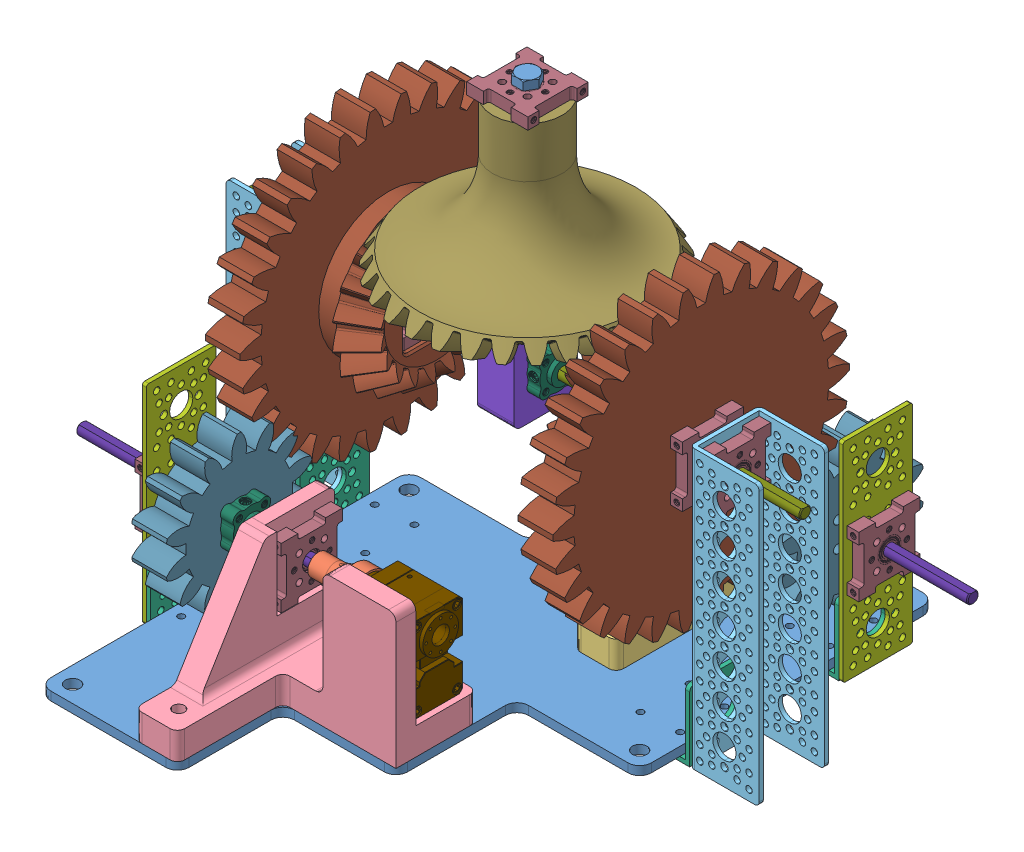
SolidWorks assembly ARMUS-103-000, configuration Défaut. Lengths in mm.
Overall size (324.91 266.38 286.64).
47 component instances, 19 part files, 72 mates.
Components (placement in the parent):
- ARMUS-103-001_V2-1: ARMUS-103-001_V2 [Default] at (0 -175.0433 0) size (204.98 4.76 285.62)
- ARMUS-103-002-1: ARMUS-103-002 [Default] at (4.7543 -124.9418 -81.7535) x (0 -0.707107 -0.707107) z (0 -0.707107 0.707107) size (22.05 28 22.05)
- ARMUS-103-003-1: ARMUS-103-003 [Défaut] at (-18.3357 -176.9255 -20.4725) size (85.41 73.38 122.11)
- ARMUS-103-004-2: ARMUS-103-004 [Défaut] at (52.1557 -176.9255 143.0345) size (85.41 73.38 122.11)
- ARMUS-103-005-2: ARMUS-103-005 [Default] at (107.9493 -29.6918 19.05) x (0 0 -1) z (0 -1 0) size (38.1 38.1 152.4)
- ARMUS-103-006-2: ARMUS-103-006 [Default] at (88.8993 -182.0918 0) x (0 0 -1) z (1 0 0) size (38.1 38.1 38.1)
- ARMUS-103-006-5: ARMUS-103-006 [Default] at (88.8993 -182.0918 -81.7535) x (0 0 -1) z (1 0 0) size (38.1 38.1 38.1)
- ARMUS-103-007-2: ARMUS-103-007 [Default] at (110.2353 -143.9918 -81.7535) x (0 -1 0) z (0 0 -1) size (114.3 2.29 38.1)
- ARMUS-103-200-1: ARMUS-103-200 [Défaut] at (0 -48.7418 17.5) x (0 1 0) z (-1 0 0) size (54 35 20)
  - ARMUS-REV4-201-1: ARMUS-REV4-201 [Défaut] at origin size (54 35 20)
  - HUB-0_25-1: HUB-0_25 [Défaut] at (-30.0172 37.5992 -6.2696) x (-1 0 0) z (0 -1 0) size (25.4 12.7 25.4)
  - hex nut_ai-2: hex nut_ai [HNUT 0.2500-20-D-N] at (19.3798 17.5 0) x (0 0.5 0.866025) z (-1 0 0) size (11.11 12.83 5.74)
- ARMUS-103-301-1: ARMUS-103-301 [Default] at (76.1993 -48.7418 0) size (50.86 161.95 162.56)
- ARMUS-103-400-1: ARMUS-103-400 [Défaut] x (0 -1 0) z (0 0 -1) size (128.27 130.43 130.79)
  - ARMUS-REV4-401-1: ARMUS-REV4-401 [Default] at origin size (93.2 130.43 130.79)
  - Bore Side Tapped Pillow Block 1.25-1: Bore Side Tapped Pillow Block 1.25 [Default] at (-58.9626 7.6184 28.3917) x (0 -1 0) z (0 0 -1) size (33.54 6.35 33.02)
  - Bore Side Tapped Pillow Block 1.25-2: Bore Side Tapped Pillow Block 1.25 [Default] at (26.0822 -28.3917 7.6184) x (0 0 -1) z (0 1 0) size (33.54 6.35 33.02)
- ARMUS-103-500-1: ARMUS-103-500 [Défaut] at (76.1993 -124.9425 -81.7542) x (1 0 0) z (0 1 0) size (28.58 79.69 81.28)
  - ARMUS-REV4-501-1: ARMUS-REV4-501 [Défaut] at origin size (19.05 79.69 81.28)
  - bore_set_screw_D_hub-1: bore_set_screw_D_hub [Défaut] at (-20.7023 -52.5937 -16.7801) x (0 -1 0.000796) z (0 0.000796 1) size (20.57 9.61 20.57)
- bore_set_screw_D_hub-1: bore_set_screw_D_hub [Défaut] at (-30.7023 -31.9192 -52.5797) x (0 0 -1) z (0 -1 0) size (20.57 9.61 20.57)
- bore_set_screw_D_hub-2: bore_set_screw_D_hub [Défaut] at (30.7023 3.8379 -16.8226) x (0 1 0) z (0 0 1) size (20.57 9.61 20.57)
- Bore Side Tapped Pillow Block 1.25-1: Bore Side Tapped Pillow Block 1.25 [Default] at (36.7834 -77.1335 -7.6184) x (0 0 1) z (0 1 0) size (33.54 6.35 33.02)
- Bore Side Tapped Pillow Block 1.25-2: Bore Side Tapped Pillow Block 1.25 [Default] at (81.0339 -77.1335 -7.6184) x (0 0 1) z (0 1 0) size (33.54 6.35 33.02)
- Bore Side Tapped Pillow Block 1.25-3: Bore Side Tapped Pillow Block 1.25 [Default] at (22.1889 -153.3335 -89.3719) x (0 0 1) z (0 1 0) size (33.54 6.35 33.02)
- Bore Side Tapped Pillow Block 1.25-4: Bore Side Tapped Pillow Block 1.25 [Default] at (96.0199 -153.3335 -89.3719) x (0 0 1) z (0 1 0) size (33.54 6.35 33.02)
- Bore Side Tapped Pillow Block 1.25-5: Bore Side Tapped Pillow Block 1.25 [Default] at (96.0199 -77.1335 -7.6184) x (0 0 1) z (0 1 0) size (33.54 6.35 33.02)
- D-Shaft 1.25x8-1: D-Shaft 1.25x8 [Default] at (0 -48.7418 0) x (0 0 1) z (1 0 0) size (6.35 5.71 304.8)
- D-Shaft 1.25x6-1: D-Shaft 1.25x6 [Default] at (86.2543 -124.9418 -81.7535) x (0 0.000796 1) z (1 0 0) size (6.35 5.71 152.4)
- XM430-W350-R-1: XM430-W350-R [Default] at (-14.6539 -136.2662 -82.2402) x (0 0 -1) z (1 0 0) size (28.5 46.5 41)
- hex bolt_ai-1: hex bolt_ai [HBOLT 0.2500-20x4.5x0.75-N] at (0 84.2906 0) x (0 -1 0) z (-0.866025 0 0.5) size (119.08 12.85 11.13)
- ARMUS-103-006-4: ARMUS-103-006 [Default] at (-88.8993 -182.0918 0) x (0 0 1) z (-1 0 0) size (38.1 38.1 38.1)
- ARMUS-103-006-6: ARMUS-103-006 [Default] at (-88.8993 -182.0918 81.7535) x (0 0 1) z (-1 0 0) size (38.1 38.1 38.1)
- XM430-W350-R-2: XM430-W350-R [Default] at (14.6539 -136.2662 82.2402) x (0 0 1) z (-1 0 0) size (28.5 46.5 41)
- ARMUS-103-002-2: ARMUS-103-002 [Default] at (-4.7543 -124.9418 81.7535) x (0 -0.707107 0.707107) z (0 -0.707107 -0.707107) size (22.05 28 22.05)
- Bore Side Tapped Pillow Block 1.25-6: Bore Side Tapped Pillow Block 1.25 [Default] at (-22.1889 -153.3335 89.3719) x (0 0 -1) z (0 1 0) size (33.54 6.35 33.02)
- Bore Side Tapped Pillow Block 1.25-7: Bore Side Tapped Pillow Block 1.25 [Default] at (-36.7834 -77.1335 7.6184) x (0 0 -1) z (0 1 0) size (33.54 6.35 33.02)
- ARMUS-103-500-2: ARMUS-103-500 [Défaut] at (-76.1993 -124.9425 81.7542) x (-1 0 0) z (0 1 0) size (28.58 79.69 81.28)
  - ARMUS-REV4-501-1: ARMUS-REV4-501 [Défaut] at origin size (19.05 79.69 81.28)
  - bore_set_screw_D_hub-1: bore_set_screw_D_hub [Défaut] at (-20.7023 -52.5937 -16.7801) x (0 -1 0.000796) z (0 0.000796 1) size (20.57 9.61 20.57)
- ARMUS-103-301-2: ARMUS-103-301 [Default] at (-76.1993 -48.7418 0) x (-1 0 0) z (0 0 -1) size (50.86 161.95 162.56)
- D-Shaft 1.25x6-2: D-Shaft 1.25x6 [Default] at (-86.2543 -124.9418 81.7535) x (0 0.000796 -1) z (-1 0 0) size (6.35 5.71 152.4)
- Bore Side Tapped Pillow Block 1.25-8: Bore Side Tapped Pillow Block 1.25 [Default] at (-81.0339 -77.1335 7.6184) x (0 0 -1) z (0 1 0) size (33.54 6.35 33.02)
- Bore Side Tapped Pillow Block 1.25-9: Bore Side Tapped Pillow Block 1.25 [Default] at (-96.0199 -77.1335 7.6184) x (0 0 -1) z (0 1 0) size (33.54 6.35 33.02)
- Bore Side Tapped Pillow Block 1.25-10: Bore Side Tapped Pillow Block 1.25 [Default] at (-96.0199 -153.3335 89.3719) x (0 0 -1) z (0 1 0) size (33.54 6.35 33.02)
- ARMUS-103-005-3: ARMUS-103-005 [Default] at (-107.9493 -29.6918 -19.05) x (0 0 1) z (0 -1 0) size (38.1 38.1 152.4)
- ARMUS-103-007-3: ARMUS-103-007 [Default] at (-110.2353 -143.9918 81.7535) x (0 -1 0) z (0 0 1) size (114.3 2.29 38.1)
Mates (geometry in assembly coordinates):
- Tangent1: tangent: circle of ARMUS-REV4-301-1; circle of ARMUS-REV4-500-1
- Coincident4: coincident aligned: plane of ARMUS-REV4-301-1 through (76.1993 -48.7418 0) normal (-1 0 0); plane of ARMUS-REV4-500-1/ARMUS-REV4-501-1 through (76.1993 -124.9425 -81.7542) normal (-1 0 0)
- Parallel3: parallel aligned: plane of ARMUS-REV4-301-1 through (76.1993 -48.7418 0) normal (0 1 0); plane of ARMUS-REV4-500-1 through (76.1993 -124.9425 -81.7542) normal (0 1 0)
- Concentric2: concentric anti-aligned: cylinder of ARMUS-REV4-301-1 through (-9.9286 -48.7418 0) axis (1 0 0) radius 6.35; cylinder of ARMUS-REV4-012-1 through (107.9493 -48.7418 0) axis (-1 0 0) radius 6.3627
- Parallel4: parallel aligned: plane of ARMUS-REV4-301-1 through (56.0789 -30.7078 -16.51) normal (0 -1 0); plane of ARMUS-REV4-012-1 through (107.9493 -182.0918 19.05) normal (0 -1 0)
- Distance1: distance = 12.7 mm anti-aligned: plane of ARMUS-REV4-301-1 through (95.2493 -48.7418 0) normal (1 0 0); plane of ARMUS-REV4-012-1 through (107.9493 -182.0918 -19.05) normal (-1 0 0)
- Concentric3: concentric anti-aligned: cylinder of ARMUS-REV4-301-1 through (-9.9286 -48.7418 0) axis (1 0 0) radius 6.35; cylinder of Bore Side Tapped Pillow Block 1.25-1 through (57.3362 -48.7418 0) axis (-1 0 0) radius 3.175
- Concentric4: concentric anti-aligned: cylinder of ARMUS-REV4-301-1 through (49.7289 -41.827 -6.9148) axis (-1 0 0) radius 1.25; cylinder of Bore Side Tapped Pillow Block 1.25-1 through (57.3489 -41.827 -6.9148) axis (1 0 0) radius 1.778
- Coincident5: coincident anti-aligned: plane of ARMUS-REV4-301-1 through (57.3489 -48.7418 0) normal (-1 0 0); plane of Bore Side Tapped Pillow Block 1.25-1 through (57.3489 -48.7418 0) normal (1 0 0)
- Concentric5: concentric anti-aligned: cylinder of ARMUS-REV4-301-1 through (-9.9286 -48.7418 0) axis (1 0 0) radius 6.35; cylinder of Bore Side Tapped Pillow Block 1.25-2 through (101.5866 -48.7418 0) axis (-1 0 0) radius 3.175
- Concentric6: concentric anti-aligned: cylinder of ARMUS-REV4-301-1 through (49.7289 -41.827 6.9148) axis (-1 0 0) radius 1.25; cylinder of Bore Side Tapped Pillow Block 1.25-2 through (101.5993 -41.827 6.9148) axis (1 0 0) radius 1.778
- Coincident6: coincident anti-aligned: plane of ARMUS-REV4-301-1 through (95.2493 -48.7418 0) normal (1 0 0); plane of Bore Side Tapped Pillow Block 1.25-2 through (95.2493 -48.7418 0) normal (-1 0 0)
- Concentric7: concentric anti-aligned: cylinder of ARMUS-REV4-012-1 through (107.9493 -163.0418 0) axis (-1 0 0) radius 6.3627; cylinder of ARMUS-REV4-010-2 through (107.9493 -163.0418 0) axis (1 0 0) radius 6.3627
- Coincident7: coincident aligned: plane of ARMUS-REV4-012-1 through (107.9493 -182.0918 19.05) normal (0 -1 0); plane of ARMUS-REV4-010-2 through (88.8993 -182.0918 0) normal (0 -1 0)
- Coincident8: coincident anti-aligned: plane of ARMUS-REV4-012-1 through (107.9493 -182.0918 -19.05) normal (-1 0 0); plane of ARMUS-REV4-010-2 through (107.9493 -179.8058 19.05) normal (1 0 0)
- Coincident9: coincident aligned: plane of ARMUS-REV4-010-2 through (88.8993 -182.0918 0) normal (0 -1 0); plane of ARMUS-REV4-010-3 through (88.8993 -182.0918 -81.7535) normal (0 -1 0)
- Coincident10: coincident aligned: plane of ARMUS-REV4-010-2 through (105.6633 -182.0918 0) normal (-1 0 0); plane of ARMUS-REV4-010-3 through (105.6633 -182.0918 -81.7535) normal (-1 0 0)
- Concentric8: concentric anti-aligned: cylinder of ARMUS-REV4-011-2 through (107.9493 -163.0418 -81.7535) axis (-1 0 0) radius 6.3627; cylinder of ARMUS-REV4-010-3 through (107.9493 -163.0418 -81.7535) axis (1 0 0) radius 6.3627
- Coincident11: coincident anti-aligned: plane of ARMUS-REV4-011-2 through (107.9493 -143.9918 -81.7535) normal (-1 0 0); plane of ARMUS-REV4-010-3 through (107.9493 -179.8058 -62.7035) normal (1 0 0)
- Concentric9: concentric anti-aligned: cylinder of ARMUS-REV4-500-1/bore_set_screw_D_hub-1 through (76.1993 -124.9418 -81.7535) axis (1 0 0) radius 3.175; cylinder of ARMUS-REV4-011-2 through (107.9493 -124.9418 -81.7535) axis (-1 0 0) radius 6.3627
- Coincident12: coincident aligned: plane of ARMUS-REV4-011-2 through (107.9493 -182.0918 -100.8035) normal (0 -1 0); plane of ARMUS-REV4-010-3 through (88.8993 -182.0918 -81.7535) normal (0 -1 0)
- Coincident16: coincident: line of ARMUS-REV4-400-1/ARMUS-REV4-401-1 through (0 73.1781 0) axis (0 -1 0)
- Coincident18: coincident: unknown of ARMUS-REV4-400-1
- Parallel5: parallel anti-aligned: plane of ARMUS-REV4-400-1/ARMUS-REV4-401-1 through (0 -12.1668 0) normal (0 -1 0)
- Coincident19: coincident: point of ARMUS-103-400-1/ARMUS-REV4-401-1; point of ARMUS-103-301-1
- Coincident21: coincident anti-aligned: plane of ARMUS-REV4-400-1 through (0 0 0) normal (0 0 -1)
- Perpendicular2: perpendicular: plane of ARMUS-REV4-400-1/ARMUS-REV4-401-1 through (0 -12.1668 0) normal (0 -1 0); plane of ARMUS-REV4-301-1 through (49.7289 -48.7418 0) normal (-1 0 0)
- Parallel6: parallel aligned: plane of ARMUS-REV4-301-1 through (76.1993 -48.7418 0) normal (1 0 0)
- Parallel7: parallel aligned: plane of ARMUS-REV4-400-1/ARMUS-REV4-401-1 through (0 -12.1668 0) normal (0 -1 0); plane of ARMUS-REV4-010-3 through (88.8993 -182.0918 -81.7535) normal (0 -1 0)
- Concentric10: concentric anti-aligned: cylinder of Bore Side Tapped Pillow Block 1.25-1 through (57.3362 -48.7418 0) axis (-1 0 0) radius 3.175; cylinder of D-Shaft 1.25x8-1 through (-152.4 -48.7418 0) axis (1 0 0) radius 3.175
- Parallel8: parallel anti-aligned: plane of ARMUS-REV4-400-1/ARMUS-REV4-401-1 through (0 -12.1668 0) normal (0 -1 0); plane of D-Shaft 1.25x8-1 through (-152.4 -46.2018 -1.905) normal (0 1 0)
- Concentric11: concentric anti-aligned: cylinder of ARMUS-REV4-200-1/HUB-0_25-1 through (6.35 -48.7418 0) axis (-1 0 0) radius 3.175; cylinder of D-Shaft 1.25x8-1 through (-152.4 -48.7418 0) axis (1 0 0) radius 3.175
- Concentric12: concentric aligned: cylinder of ARMUS-REV4-400-1/ARMUS-REV4-401-1 through (0 -128.2701 0) axis (0 1 0) radius 6.35; cylinder of ARMUS-REV4-200-1/ARMUS-REV4-201-1 through (0 -43.222 0) axis (0 1 0) radius 3.175
- Concentric13: concentric aligned: cylinder of bore_set_screw_D_hub-1 through (-10 -48.7418 0) axis (1 0 0) radius 3.175; cylinder of D-Shaft 1.25x8-1 through (-152.4 -48.7418 0) axis (1 0 0) radius 3.175
- Concentric14: concentric aligned: cylinder of ARMUS-REV4-200-1/ARMUS-REV4-201-1 through (15.0289 -41.827 -6.9148) axis (-1 0 0) radius 1.778; cylinder of bore_set_screw_D_hub-1 through (-10 -41.827 -6.9148) axis (-1 0 0) radius 3.3722
- Coincident23: coincident anti-aligned: plane of ARMUS-REV4-200-1/ARMUS-REV4-201-1 through (-10 -18.7418 -17.5) normal (-1 0 0); plane of bore_set_screw_D_hub-1 through (-10 -45.2844 3.4574) normal (1 0 0)
- Coincident24: coincident anti-aligned: plane of ARMUS-REV4-200-1/ARMUS-REV4-201-1 through (10 -18.7418 -17.5) normal (1 0 0); plane of bore_set_screw_D_hub-2 through (10 -52.1992 -3.4574) normal (-1 0 0)
- Concentric15: concentric anti-aligned: cylinder of ARMUS-REV4-200-1/ARMUS-REV4-201-1 through (15.0289 -55.6566 -6.9148) axis (-1 0 0) radius 1.778; cylinder of bore_set_screw_D_hub-2 through (10 -55.6566 -6.9148) axis (1 0 0) radius 3.3722
- Concentric16: concentric anti-aligned: cylinder of bore_set_screw_D_hub-2 through (10 -48.7418 0) axis (-1 0 0) radius 3.175; cylinder of D-Shaft 1.25x8-1 through (-152.4 -48.7418 0) axis (1 0 0) radius 3.175
- Width1: width aligned: plane of D-Shaft 1.25x8-1 through (-152.4 -48.7418 0) normal (-1 0 0); plane of ARMUS-REV4-200-1/ARMUS-REV4-201-1 through (152.4 -48.7418 0) normal (1 0 0); plane of D-Shaft 1.25x8-1 through (-10 -18.7418 -17.5) normal (-1 0 0); plane of ARMUS-REV4-200-1/ARMUS-REV4-201-1 through (10 -18.7418 -17.5) normal (1 0 0)
- Concentric17: concentric anti-aligned: cylinder of ARMUS-REV4-500-1/bore_set_screw_D_hub-1 through (76.1993 -124.9418 -81.7535) axis (1 0 0) radius 3.175; cylinder of ARMUS-REV4-004-1 through (83.1653 -124.9418 -81.7535) axis (-1 0 0) radius 4.5
- Parallel9: parallel anti-aligned: plane of ARMUS-REV4-010-3 through (88.8993 -179.8058 -81.7535) normal (0 1 0); plane of ARMUS-REV4-004-1 through (-84.6557 -175.0433 114.7662) normal (0 -1 0)
- Distance2: distance = 19.05 mm anti-aligned: plane of ARMUS-REV4-500-1/bore_set_screw_D_hub-1 through (69.2143 -128.4019 -85.2081) normal (-1 0 0); plane of ARMUS-REV4-004-1 through (50.1643 -101.6652 -100.5825) normal (1 0 0)
- Concentric18: concentric aligned: cylinder of ARMUS-REV4-004-1 through (-9.2457 -175.0433 -89.7535) axis (0 1 0) radius 1; cylinder of XM430-W350-R-1 through (-9.2457 -157.1918 -89.7535) axis (0 1 0) radius 1
- Concentric19: concentric aligned: cylinder of ARMUS-REV4-004-1 through (-21.2457 -175.0433 -89.7535) axis (0 1 0) radius 1; cylinder of XM430-W350-R-1 through (-21.2457 -157.1918 -89.7535) axis (0 1 0) radius 1
- Coincident25: coincident anti-aligned: plane of ARMUS-REV4-004-1 through (-35.2457 -160.1918 -56.2023) normal (0 1 0); plane of XM430-W350-R-1 through (-6.7457 -160.1918 -67.5035) normal (0 -1 0)
- Concentric20: concentric anti-aligned: cylinder of ARMUS-REV4-004-1 through (83.1653 -124.9418 -81.7535) axis (-1 0 0) radius 4.5; cylinder of XM430-W350-R-1 through (4.7543 -124.9418 -81.7535) axis (1 0 0) radius 9.75
- Concentric21: concentric anti-aligned: cylinder of XM430-W350-R-1 through (4.7543 -124.9418 -81.7535) axis (1 0 0) radius 9.75; cylinder of ARMUS-REV4-002-1 through (12.7543 -124.9418 -81.7535) axis (-1 0 0) radius 10.75
- Concentric22: concentric anti-aligned: circle of XM430-W350-R-1; cylinder of ARMUS-REV4-002-1 through (12.7543 -116.9418 -81.7535) axis (-1 0 0) radius 1
- Coincident26: coincident anti-aligned: plane of XM430-W350-R-1 through (4.7543 -124.9418 -81.7535) normal (1 0 0); plane of ARMUS-REV4-002-1 through (4.7543 -124.9418 -81.7535) normal (-1 0 0)
- Concentric23: concentric anti-aligned: cylinder of ARMUS-REV4-004-1 through (83.1653 -124.9418 -81.7535) axis (-1 0 0) radius 4.5; cylinder of D-Shaft 1.25x6-1 through (10.0543 -124.9418 -81.7535) axis (1 0 0) radius 3.175
- Parallel10: parallel aligned: plane of ARMUS-REV4-500-1/bore_set_screw_D_hub-1 through (72.7068 -116.0061 -81.7606) normal (0 1 -0.000796); plane of D-Shaft 1.25x6-1 through (10.0543 -122.4033 -83.6605) normal (0 1 -0.000796)
- Coincident28: coincident aligned: circle of ARMUS-REV4-002-1; plane of D-Shaft 1.25x6-1 through (10.0543 -124.9418 -81.7535) normal (-1 0 0)
- Concentric24: concentric anti-aligned: cylinder of ARMUS-REV4-004-1 through (50.1643 -118.027 -88.6683) axis (-1 0 0) radius 1.778; cylinder of Bore Side Tapped Pillow Block 1.25-3 through (42.7543 -118.027 -88.6683) axis (1 0 0) radius 1.778
- Coincident30: coincident anti-aligned: plane of ARMUS-REV4-004-1 through (42.7543 -101.6652 -62.5625) normal (-1 0 0); plane of Bore Side Tapped Pillow Block 1.25-3 through (42.7543 -124.9418 -81.7535) normal (1 0 0)
- Concentric25: concentric anti-aligned: cylinder of ARMUS-REV4-004-1 through (50.1643 -131.8566 -88.6683) axis (-1 0 0) radius 1.778; cylinder of Bore Side Tapped Pillow Block 1.25-3 through (42.7543 -131.8566 -88.6683) axis (1 0 0) radius 1.778
- Concentric26: concentric aligned: cylinder of ARMUS-REV4-011-2 through (107.9493 -124.9418 -81.7535) axis (-1 0 0) radius 6.3627; cylinder of Bore Side Tapped Pillow Block 1.25-4 through (116.5726 -124.9418 -81.7535) axis (-1 0 0) radius 3.175
- Coincident31: coincident anti-aligned: plane of ARMUS-REV4-011-2 through (110.2353 -143.9918 -81.7535) normal (1 0 0); plane of Bore Side Tapped Pillow Block 1.25-4 through (110.2353 -124.9418 -81.7535) normal (-1 0 0)
- Concentric27: concentric anti-aligned: cylinder of ARMUS-REV4-011-2 through (107.9493 -118.027 -74.8387) axis (-1 0 0) radius 1.778; cylinder of Bore Side Tapped Pillow Block 1.25-4 through (116.5853 -118.027 -74.8387) axis (1 0 0) radius 1.778
- Coincident32: coincident anti-aligned: plane of ARMUS-REV4-012-1 through (110.2353 -182.0918 16.764) normal (1 0 0); plane of Bore Side Tapped Pillow Block 1.25-5 through (110.2353 -48.7418 0) normal (-1 0 0)
- Concentric28: concentric aligned: cylinder of ARMUS-REV4-012-1 through (107.9493 -48.7418 0) axis (-1 0 0) radius 6.3627; cylinder of Bore Side Tapped Pillow Block 1.25-5 through (116.5726 -48.7418 0) axis (-1 0 0) radius 3.175
- Concentric29: concentric anti-aligned: cylinder of ARMUS-REV4-012-1 through (107.9493 -41.827 6.9148) axis (-1 0 0) radius 1.778; cylinder of Bore Side Tapped Pillow Block 1.25-5 through (116.5853 -41.827 6.9148) axis (1 0 0) radius 1.778
- Coincident33: coincident anti-aligned: plane of ARMUS-REV4-400-1/Bore Side Tapped Pillow Block 1.25-1 through (0 79.5154 0) normal (0 1 0); plane of hex bolt_ai-1 through (3.2116 79.5154 5.5626) normal (0 -1 0)
- Concentric30: concentric anti-aligned: cylinder of ARMUS-REV4-400-1/Bore Side Tapped Pillow Block 1.25-1 through (0 79.5154 0) axis (0 -1 0) radius 3.175; cylinder of hex bolt_ai-1 through (0 84.2906 0) axis (0 1 0) radius 3.175
- Parallel11: parallel aligned: plane of ARMUS-REV4-400-1/Bore Side Tapped Pillow Block 1.25-1 through (7.62 79.5281 -13.6449) normal (0 0 -1); plane of hex bolt_ai-1 through (3.2116 79.5154 -5.5626) normal (0 0 -1)
- Concentric31: concentric aligned: cylinder of XM430-W350-R-2 through (21.2457 -157.1918 73.7535) axis (0 1 0) radius 1; cylinder of ARMUS-REV4-005-1 through (21.2457 -175.0433 73.7535) axis (0 1 0) radius 1
- Concentric32: concentric aligned: cylinder of XM430-W350-R-2 through (9.2457 -157.1918 73.7535) axis (0 1 0) radius 1; cylinder of ARMUS-REV4-005-1 through (9.2457 -175.0433 73.7535) axis (0 1 0) radius 1
- Coincident34: coincident anti-aligned: plane of XM430-W350-R-2 through (6.7457 -160.1918 67.5035) normal (0 -1 0); plane of ARMUS-REV4-005-1 through (35.2457 -160.1918 107.3047) normal (0 1 0)
- Coincident35: coincident anti-aligned: plane of ARMUS-REV4-010-2 through (88.8993 -179.8058 0) normal (0 1 0); plane of ARMUS-REV4-001_V2-1 through (0 -179.8058 0) normal (0 -1 0)
- Coincident36: coincident aligned: plane of ARMUS-REV4-001_V2-1 through (0 -175.0433 0) normal (0 0 1)
- Parallel12: parallel aligned: plane of ARMUS-REV4-001_V2-1 through (0 -175.0433 0) normal (0 1 0)
- Coincident37: coincident aligned: plane of ARMUS-REV4-001_V2-1 through (0 -175.0433 0) normal (1 0 0)
